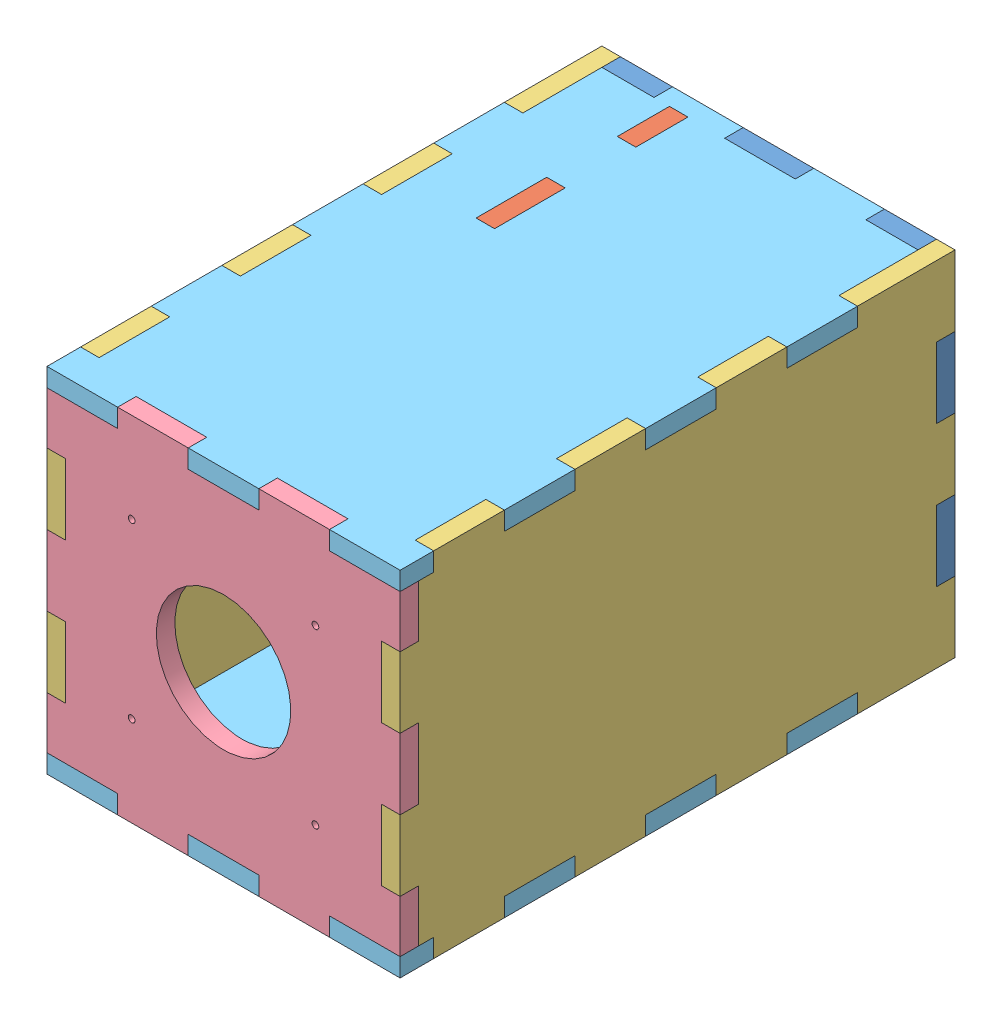
SolidWorks assembly EnsamblajeCaja, configuration Predeterminado. Lengths in mm.
Overall size (105 105 165).
8 component instances, 6 part files, 18 mates.
Components (placement in the parent):
- Fondo-1: Fondo [Predeterminado] at (6.2412 -12.748 98.5) size (105 105 5.5)
- Lateral Servo-2: Lateral Servo [Predeterminado] at (-15.1688 -12.748 151) x (0 0 -1) z (-1 0 0) size (63 105 5.5)
- Lateral estándar-3: Lateral estándar [Predeterminado] at (-46.2588 -6.393 201) x (0 0 -1) z (1 0 0) size (165 105 5.5)
- Lateral estándar-4: Lateral estándar [Predeterminado] at (53.2412 -6.393 201) x (0 0 -1) z (1 0 0) size (165 105 5.5)
- Pieza1^EnsamblajeCaja-1: Pieza1^EnsamblajeCaja [Predeterminado] at origin (virtual)
- Tapa-2: Tapa [Predeterminado] at (6.2412 -12.748 258) x (0 -1 0) z (0 0 1) size (105 105 5.5)
- Trasero-1: Trasero [Predeterminado] at (7.397 -65.248 200.7096) x (0 0 -1) z (0 1 0) size (165 105 5.5)
- Trasero-2: Trasero [Predeterminado] at (7.397 34.252 200.7096) x (0 0 -1) z (0 1 0) size (165 105 5.5)
Mates (geometry in assembly coordinates):
- Coincidente1: coincident anti-aligned: plane of Fondo-1 through (-20.6688 -44.248 104) normal (1 0 0); plane of Lateral Servo-2 through (-20.6688 -12.748 151) normal (-1 0 0)
- Coincidente2: coincident aligned: plane of Fondo-1 through (6.2412 -12.748 98.5) normal (0 0 -1); plane of Lateral Servo-2 through (-15.1688 -12.748 98.5) normal (0 0 -1)
- Coincidente3: coincident anti-aligned: plane of Fondo-1 through (-20.6688 18.752 104) normal (0 -1 0); plane of Lateral Servo-2 through (-20.6688 18.752 104) normal (0 1 0)
- Coincidente4: coincident aligned: plane of Fondo-1 through (-46.2588 -12.748 98.5) normal (-1 0 0); plane of Lateral estándar-3 through (-46.2588 -6.393 201) normal (-1 0 0)
- Coincidente5: coincident aligned: plane of Fondo-1 through (6.2412 -12.748 98.5) normal (0 0 -1); plane of Lateral estándar-3 through (-46.2588 -6.393 98.5) normal (0 0 -1)
- Coincidente6: coincident aligned: plane of Fondo-1 through (6.2412 -65.248 98.5) normal (0 -1 0); plane of Lateral estándar-3 through (-46.2588 -65.248 201) normal (0 -1 0)
- Coincidente7: coincident aligned: plane of Fondo-1 through (58.7412 -12.748 98.5) normal (1 0 0); plane of Lateral estándar-4 through (58.7412 -6.393 201) normal (1 0 0)
- Coincidente8: coincident aligned: plane of Fondo-1 through (6.2412 -12.748 98.5) normal (0 0 -1); plane of Lateral estándar-4 through (53.2412 -6.393 98.5) normal (0 0 -1)
- Coincidente9: coincident aligned: plane of Fondo-1 through (6.2412 39.752 98.5) normal (0 1 0); plane of Lateral estándar-4 through (53.2412 39.752 201) normal (0 1 0)
- Coincidente16: coincident aligned: plane of Lateral estándar-3 through (-46.2588 -6.393 201) normal (-1 0 0); plane of Tapa-2 through (-46.2588 -12.748 258) normal (-1 0 0)
- Coincidente17: coincident aligned: plane of Lateral estándar-3 through (-46.2588 -6.393 263.5) normal (0 0 1); plane of Tapa-2 through (6.2412 -12.748 263.5) normal (0 0 1)
- Coincidente18: coincident aligned: plane of Lateral estándar-3 through (-46.2588 -65.248 201) normal (0 -1 0); plane of Tapa-2 through (6.2412 -65.248 258) normal (0 -1 0)
- Coincidente19: coincident aligned: plane of Lateral estándar-4 through (53.2412 -65.248 201) normal (0 -1 0); plane of Trasero-1 through (7.397 -65.248 200.7096) normal (0 -1 0)
- Coincidente20: coincident aligned: plane of Tapa-2 through (6.2412 -12.748 263.5) normal (0 0 1); plane of Trasero-1 through (7.397 -65.248 263.5) normal (0 0 1)
- Coincidente21: coincident aligned: plane of Tapa-2 through (58.7412 -12.748 258) normal (1 0 0); plane of Trasero-1 through (58.7412 -65.248 200.7096) normal (1 0 0)
- Coincidente22: coincident aligned: plane of Tapa-2 through (6.2412 39.752 258) normal (0 1 0); plane of Trasero-2 through (7.397 39.752 200.7096) normal (0 1 0)
- Coincidente23: coincident aligned: plane of Lateral estándar-4 through (58.7412 -6.393 201) normal (1 0 0); plane of Trasero-2 through (58.7412 34.252 200.7096) normal (1 0 0)
- Coincidente24: coincident aligned: plane of Tapa-2 through (6.2412 -12.748 263.5) normal (0 0 1); plane of Trasero-2 through (7.397 34.252 263.5) normal (0 0 1)
